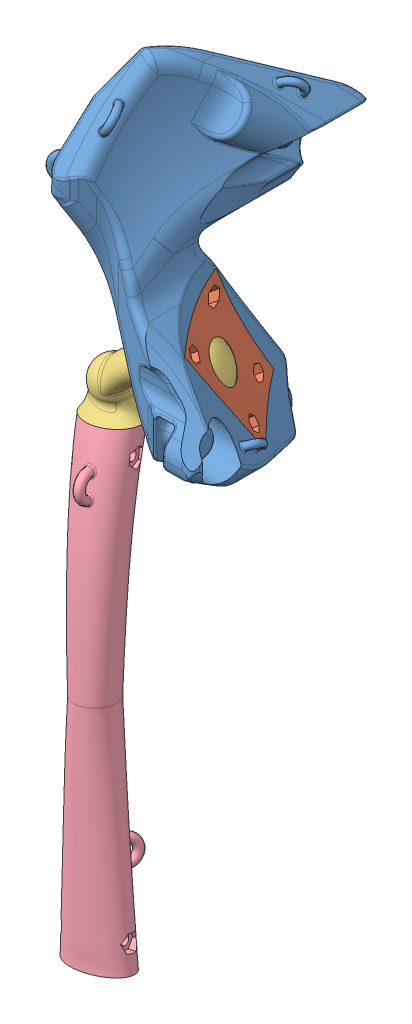
SolidWorks assembly Assem2, configuration Default. Lengths in mm.
Overall size (258.81 543.44 288.6).
4 component instances, 4 part files, 7 mates.
Components (placement in the parent):
- hip ball_socket-1: hip ball_socket [Default] at (-98.0448 48.0389 -121.5165) size (224.34 274.02 288.6)
- illiumbackplate-1: illiumbackplate [Default] at (-147.5212 13.5879 -85.5581) x (-0.420371 -0.292709 -0.858842) z (0.70481 0.490767 -0.51224) size (102.05 115.23 35.74)
- ball3-1: ball3 [Default] at (-93.6106 -11.5363 -35.4514) x (0.201586 0.056171 0.977859) z (-0.9664 -0.15115 0.207906) size (50.29 101.97 98.86)
- femor bone mirror-1: femor bone mirror [Default] at (-82.4624 -484.9277 7.8594) x (-0.151591 -0.086922 -0.984614) z (-0.970931 -0.173582 0.164808) size (63.87 307.72 68.31)
Mates (geometry in assembly coordinates):
- Coincident1: coincident: plane of hip ball_socket-1 through (-121.1631 23.0629 -40.2131) normal (0.66191 -0.195211 0.723718); plane of illiumbackplate-1 through (-20.5172 93.1438 -113.3603) normal (-0.66191 0.195211 -0.723718)
- Coincident2: coincident: plane of hip ball_socket-1 through (-101.3178 -42.974 -76.1759) normal (-0.255182 0.849141 0.46243); plane of illiumbackplate-1 through (-0.6719 27.1068 -149.3231) normal (0.255182 -0.849141 -0.46243)
- Coincident3: coincident: plane of hip ball_socket-1 through (-147.5212 13.5879 -85.5581) normal (0.70481 0.490767 -0.51224); plane of illiumbackplate-1 through (-147.5212 13.5879 -85.5581) normal (-0.70481 -0.490767 0.51224)
- Concentric3: concentric: sphere of illiumbackplate-1; sphere of ball3-1
- Coincident6: coincident: plane of ball3-1 through (-152.7397 -59.1987 -38.83) normal (-0.12394 -0.317172 -0.940234); plane of femor bone mirror-1 through (-152.7397 -59.1987 -38.83) normal (0.12394 0.317172 0.940234)
- Coincident7: coincident: plane of ball3-1 through (-134.0063 -57.5333 -41.8613) normal (0.983381 0.087424 -0.159119); plane of femor bone mirror-1 through (-134.0063 -57.5333 -41.8613) normal (-0.983381 -0.087424 0.159119)
- Coincident8: coincident: plane of ball3-1 through (-120.4113 -93.3584 -11.533) normal (0.09991 -0.992372 0.072225); plane of femor bone mirror-1 through (-120.4113 -93.3584 -11.533) normal (-0.09991 0.992372 -0.072225)
